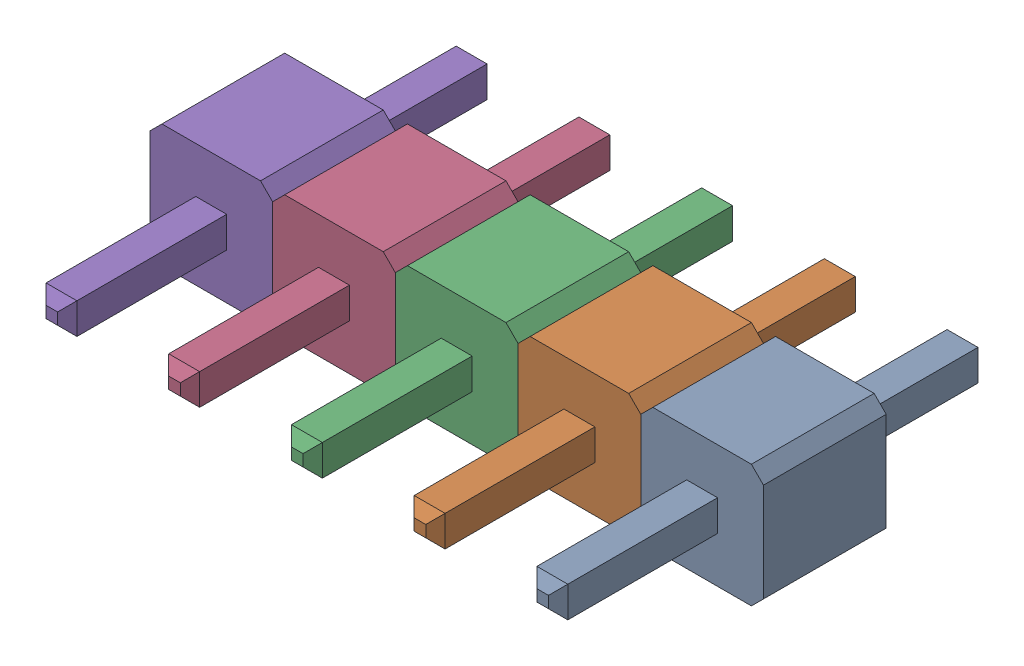
SolidWorks assembly J2, configuration Default. Lengths in mm.
Overall size (12.7 2.54 8.89).
6 component instances, 1 part files, 0 mates.
Components (placement in the parent):
- PEC05SAAN-1: PEC05SAAN [Default] at (49.2759 1.5239 0) x (-1 0 0) z (0 0 1) size (12.7 2.54 8.89)
  - PEC05SAAN_1-1: PEC05SAAN_1 [Default] at origin size (2.54 2.54 8.89)
  - PEC05SAAN_1-2: PEC05SAAN_1 [Default] at (2.54 0 0) size (2.54 2.54 8.89)
  - PEC05SAAN_1-3: PEC05SAAN_1 [Default] at (5.08 0 0) size (2.54 2.54 8.89)
  - PEC05SAAN_1-4: PEC05SAAN_1 [Default] at (7.62 0 0) size (2.54 2.54 8.89)
  - PEC05SAAN_1-5: PEC05SAAN_1 [Default] at (10.16 0 0) size (2.54 2.54 8.89)
